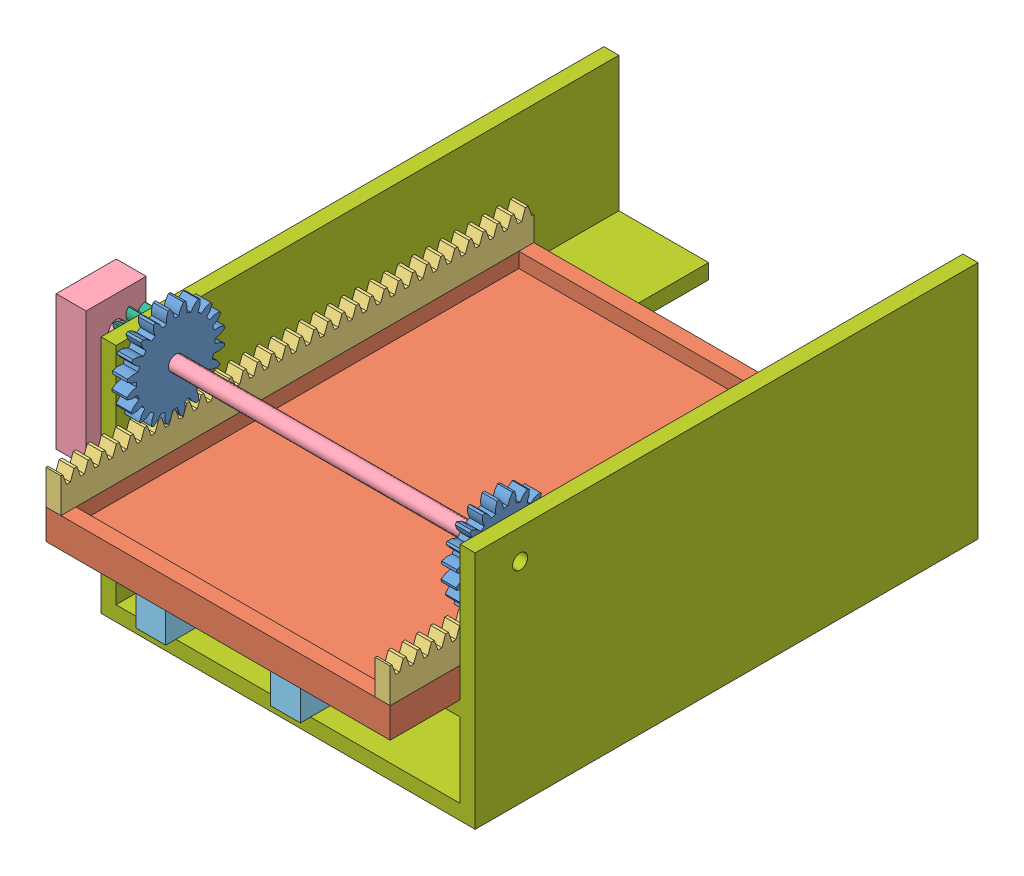
SolidWorks assembly Ensamblaje1, configuration Predeterminado. Lengths in mm.
Overall size (145 144.54 260.26).
11 component instances, 7 part files, 18 mates.
Components (placement in the parent):
- spur gear_am1-3: spur gear_am1 [Metric - Spur gear 1.5M 20T 20PA 5FW ---S20N75H50L5N] at (25 35 572.4357) x (1 0 0) z (0 -0.957172 -0.289521) size (5 123.35 32.71)
- Ensamblaje2^Ensamblaje1-1: Ensamblaje2^Ensamblaje1 [Predeterminado] at (25 0 610.841) size (115 63.47 159.89) (virtual)
  - base para hojas-1: base para hojas [Predeterminado] at origin size (115 10 158)
  - cremallera base hojas-1: cremallera base hojas [Metric - Rack-spur - rectangular 1.5M 20PA 5FW 10PH 158L---SAll] at (0 10 -158) x (0 0 1) z (-1 0 0) size (159.89 53.47 5)
  - cremallera base hojas-2: cremallera base hojas [Metric - Rack-spur - rectangular 1.5M 20PA 5FW 10PH 158L---SAll] at (110 10 -158) x (0 0 1) z (-1 0 0) size (159.89 53.47 5)
- servo eje-2: servo eje [Predeterminado] at (10 35 572.4357) x (0 -1 0) z (0 0 1) size (45 140 20.09)
- riel base-1: riel base [Predeterminado] at (55 -10 610.841) size (10 10 158)
- riel base-2: riel base [Predeterminado] at (100 -10 610.841) size (10 10 158)
- spur gear_am1-4: spur gear_am1 [Metric - Spur gear 1.5M 20T 20PA 5FW ---S20N75H50L5N] at (135 35 572.4357) x (1 0 0) z (0 -0.999857 0.016895) size (5 123.35 32.71)
- engranaje servo 1-1: engranaje servo 1 [Metric - Spur gear 1.5M 10T 20PA 5FW ---S10N75H50L5N] at (14.8423 35 572.4357) x (1 0 0) z (0 0.775442 0.631419) size (5 115.62 18)
- base general-1: base general [Predeterminado] at (20 -35 587.4357) size (125 80 168)
Mates (geometry in assembly coordinates):
- Coincidente45: coincident aligned: circle of spur gear_am1-3; cylinder of servo eje-2 through (30 35 572.4357) axis (-1 0 0) radius 2.5
- Coincidente46: coincident aligned: plane of Ensamblaje2^Ensamblaje1-1/base para hojas-1 through (25 0 610.841) normal (0 -1 0); plane of servo eje-2 through (0 0 582.4357) normal (0 -1 0)
- Coincidente48: coincident anti-aligned: plane of Ensamblaje2^Ensamblaje1-1/base para hojas-1 through (25 0 610.841) normal (0 -1 0); plane of assembly through (0 0 0) normal (0 1 0)
- Coincidente50: coincident anti-aligned: plane of servo eje-2 through (0 35 572.4357) normal (-1 0 0); plane of assembly through (0 0 0) normal (1 0 0)
- Coincidente53: coincident aligned: plane of spur gear_am1-3 through (25 35 572.4357) normal (-1 0 0); plane of Ensamblaje2^Ensamblaje1-1/base para hojas-1 through (25 10 610.841) normal (-1 0 0)
- Relación de posición del piñón del engranaje de cremallera8: rack pinion = 30 mm: line of Ensamblaje2^Ensamblaje1-1/cremallera base hojas-1 through (30 10 452.841) axis (0 0 1); circle of spur gear_am1-3
- Coincidente54: coincident anti-aligned: plane of Ensamblaje2^Ensamblaje1-1/base para hojas-1 through (25 0 610.841) normal (0 -1 0); plane of riel base-1 through (55 0 610.841) normal (0 1 0)
- Coincidente55: coincident aligned: plane of Ensamblaje2^Ensamblaje1-1/base para hojas-1 through (25 10 610.841) normal (0 0 1); plane of riel base-1 through (55 0 610.841) normal (0 0 1)
- Coincidente56: coincident anti-aligned: plane of Ensamblaje2^Ensamblaje1-1/base para hojas-1 through (25 0 610.841) normal (0 -1 0); plane of riel base-2 through (100 0 610.841) normal (0 1 0)
- Coincidente57: coincident aligned: plane of Ensamblaje2^Ensamblaje1-1/base para hojas-1 through (25 10 452.841) normal (0 0 -1); plane of riel base-2 through (100 0 452.841) normal (0 0 -1)
- Concéntrica2: concentric aligned: cylinder of servo eje-2 through (30 35 572.4357) axis (-1 0 0) radius 2.5; cylinder of spur gear_am1-4 through (185.0001 35 572.4357) axis (-1 0 0) radius 2.5
- Coincidente65: coincident aligned: plane of servo eje-2 through (140 35 572.4357) normal (1 0 0); plane of spur gear_am1-4 through (140 35 572.4357) normal (1 0 0)
- Coincidente66: coincident aligned: plane of Ensamblaje2^Ensamblaje1-1/cremallera base hojas-2 through (140 21.5 452.841) normal (1 0 0); plane of spur gear_am1-4 through (140 35 572.4357) normal (1 0 0)
- Relación de posición del piñón del engranaje de cremallera9: rack pinion = 30 mm: line of Ensamblaje2^Ensamblaje1-1/cremallera base hojas-2 through (140 10 452.841) axis (0 0 1); circle of spur gear_am1-4
- Concéntrica3: concentric aligned: cylinder of servo eje-2 through (30 35 572.4357) axis (-1 0 0) radius 2.5; cylinder of engranaje servo 1-1 through (64.8424 35 572.4357) axis (-1 0 0) radius 2.5
- Coincidente68: coincident anti-aligned: plane of Ensamblaje2^Ensamblaje1-1/base para hojas-1 through (25 0 610.841) normal (0 -1 0); plane of base general-1 through (55 0 587.4357) normal (0 1 0)
- Coincidente69: coincident anti-aligned: plane of Ensamblaje2^Ensamblaje1-1/base para hojas-1 through (140 10 610.841) normal (1 0 0); plane of base general-1 through (140 45 419.4357) normal (-1 0 0)
- Coincidente71: coincident anti-aligned: cylinder of servo eje-2 through (30 35 572.4357) axis (-1 0 0) radius 2.5; circle of base general-1
